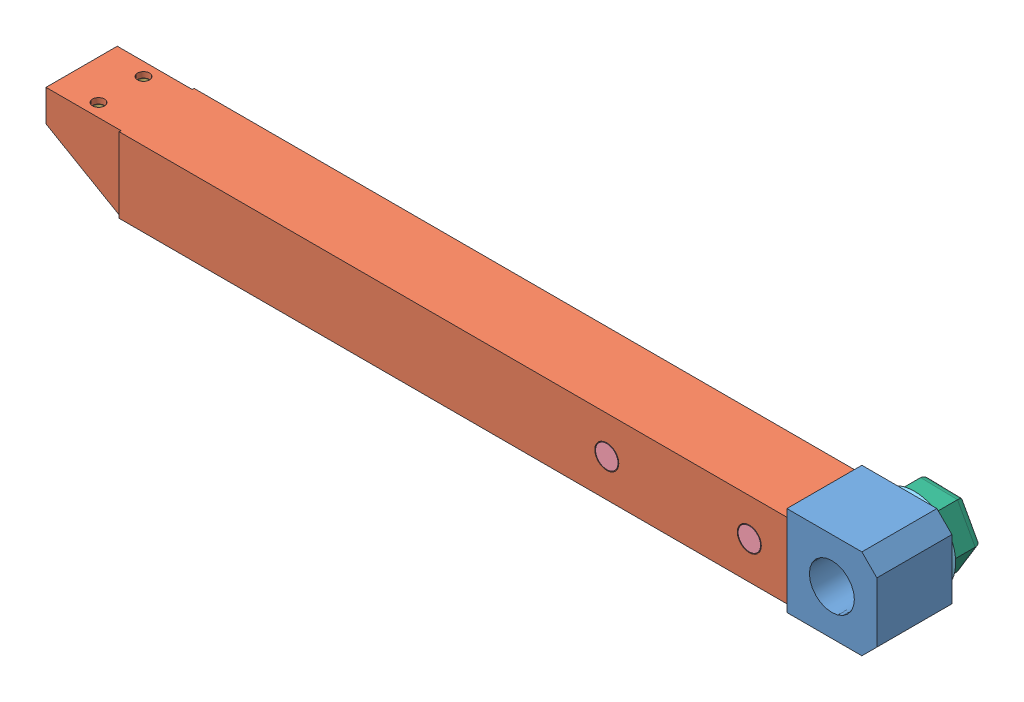
SolidWorks assembly Bras_2, configuration Défaut. Lengths in mm.
Overall size (224.37 28.75 30.4).
7 component instances, 6 part files, 15 mates.
Components (placement in the parent):
- Pièce2_support_bras-1: Pièce2_support_bras [Défaut] at origin size (78 24 20)
- Pièce3_Bras-1: Pièce3_Bras [Défaut] at (-101 10 10) x (-1 0 0) z (0 -1 0) size (198 20 20)
- Pièce3_EcrouBras-1: Pièce3_EcrouBras [Défaut] at (-199.5 5.5 10) x (0 0 -1) z (0 1 0) size (17 8 3)
- Pièce3_VisBras-1: Pièce3_VisBras [Défaut] at (-60 0 0) size (6 6 20)
- Pièce3_VisBras-2: Pièce3_VisBras [Défaut] at (-22 0 0) size (6 6 20)
- Pièce1_Rendelle-1: Pièce1_Rendelle [Défaut] x (-0.923728 -0.383049 0) z (0 0 -1) size (22 22 2)
- Pièce2_EcrouBras-1: Pièce2_EcrouBras [Défaut] at (0 0 -10.4) x (-0.021598 -0.999767 0) z (0 0 -1) size (17 19.63 8.4)
Mates (geometry in assembly coordinates):
- Coïncidente1: coincident anti-aligned: plane of Pièce3_Bras-1 through (-101 8.5 10) normal (0 -1 0); plane of Pièce3_EcrouBras-1 through (-199.5 8.5 10) normal (0 1 0)
- Coaxiale3: concentric anti-aligned: cylinder of Pièce3_Bras-1 through (-199.5 -14 4) axis (0 1 0) radius 1.6; cylinder of Pièce3_EcrouBras-1 through (-199.5 8.5 4) axis (0 -1 0) radius 1.5
- Coaxiale4: concentric anti-aligned: cylinder of Pièce3_Bras-1 through (-199.5 -14 16) axis (0 1 0) radius 1.6; cylinder of Pièce3_EcrouBras-1 through (-199.5 8.5 16) axis (0 -1 0) radius 1.5
- Coaxiale9: concentric anti-aligned: cylinder of Pièce2_support_bras-1 through (-60 0 20) axis (0 0 -1) radius 3; cylinder of Pièce3_Bras-1 through (-60 0 -14) axis (0 0 1) radius 3.2
- Coaxiale10: concentric anti-aligned: cylinder of Pièce2_support_bras-1 through (-22 0 20) axis (0 0 -1) radius 3; cylinder of Pièce3_Bras-1 through (-22 0 -14) axis (0 0 1) radius 3.2
- Coïncidente5: coincident anti-aligned: plane of Pièce2_support_bras-1 through (0 0 18.5) normal (0 0 1); plane of Pièce3_Bras-1 through (-190 8.5 18.5) normal (0 0 -1)
- Coaxiale11: concentric aligned: cylinder of Pièce2_support_bras-1 through (-60 0 20) axis (0 0 -1) radius 3; cylinder of Pièce3_VisBras-1 through (-60 0 20) axis (0 0 -1) radius 3
- Coïncidente6: coincident aligned: plane of Pièce3_Bras-1 through (-101 -10 0) normal (0 0 -1); plane of Pièce3_VisBras-1 through (-60 0 0) normal (0 0 -1)
- Coaxiale12: concentric aligned: cylinder of Pièce2_support_bras-1 through (-22 0 20) axis (0 0 -1) radius 3; cylinder of Pièce3_VisBras-2 through (-22 0 20) axis (0 0 -1) radius 3
- Coïncidente7: coincident aligned: plane of Pièce3_Bras-1 through (-101 -10 0) normal (0 0 -1); plane of Pièce3_VisBras-2 through (-22 0 0) normal (0 0 -1)
- Coïncidente8: coincident anti-aligned: plane of Pièce2_support_bras-1 through (0 0 0) normal (0 0 -1); plane of Pièce1_Rendelle-1 through (0 0 0) normal (0 0 1)
- Coaxiale13: concentric anti-aligned: cylinder of Pièce2_support_bras-1 through (0 0 20) axis (0 0 -1) radius 6; cylinder of Pièce1_Rendelle-1 through (0 0 -2) axis (0 0 1) radius 5
- Coïncidente9: coincident aligned: plane of Pièce1_Rendelle-1 through (0 0 -2) normal (0 0 -1); plane of Pièce2_EcrouBras-1 through (0 0 -2) normal (0 0 -1)
- Coaxiale14: concentric anti-aligned: cylinder of Pièce2_support_bras-1 through (0 0 20) axis (0 0 -1) radius 6; cylinder of Pièce2_EcrouBras-1 through (0 0 -2) axis (0 0 1) radius 5
- Coïncidente10: coincident anti-aligned: plane of Pièce1_Rendelle-1 through (0 0 -2) normal (0 0 -1); plane of Pièce2_EcrouBras-1 through (0 0 -2) normal (0 0 1)
